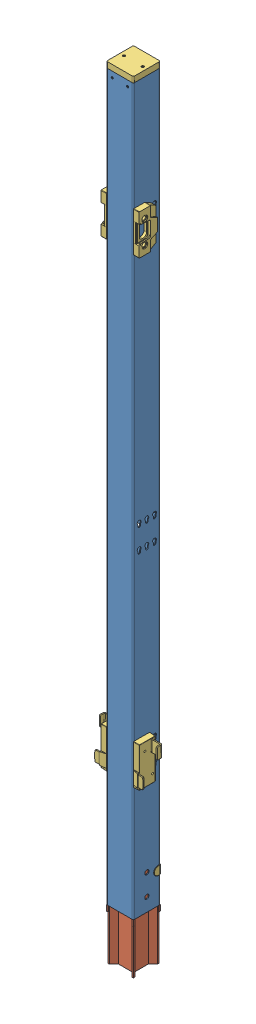
SolidWorks assembly E13-190-Axelent, configuration Default. Lengths in mm.
Overall size (150.99 2032.5 74.3).
3 component instances, 3 part files, 0 mates.
Components (placement in the parent):
- P03-XXX(1885)-1: P03-XXX(1885) [Default] at origin size (70 1885 70)
- B00-042-KR-1-1: B00-042-KR-1 [Default] at (0 -7.5 0) size (70 250 70)
- A-0025004-1: A-0025004 [Default] at (0 -100 0) size (150.99 1831.48 74.3)
